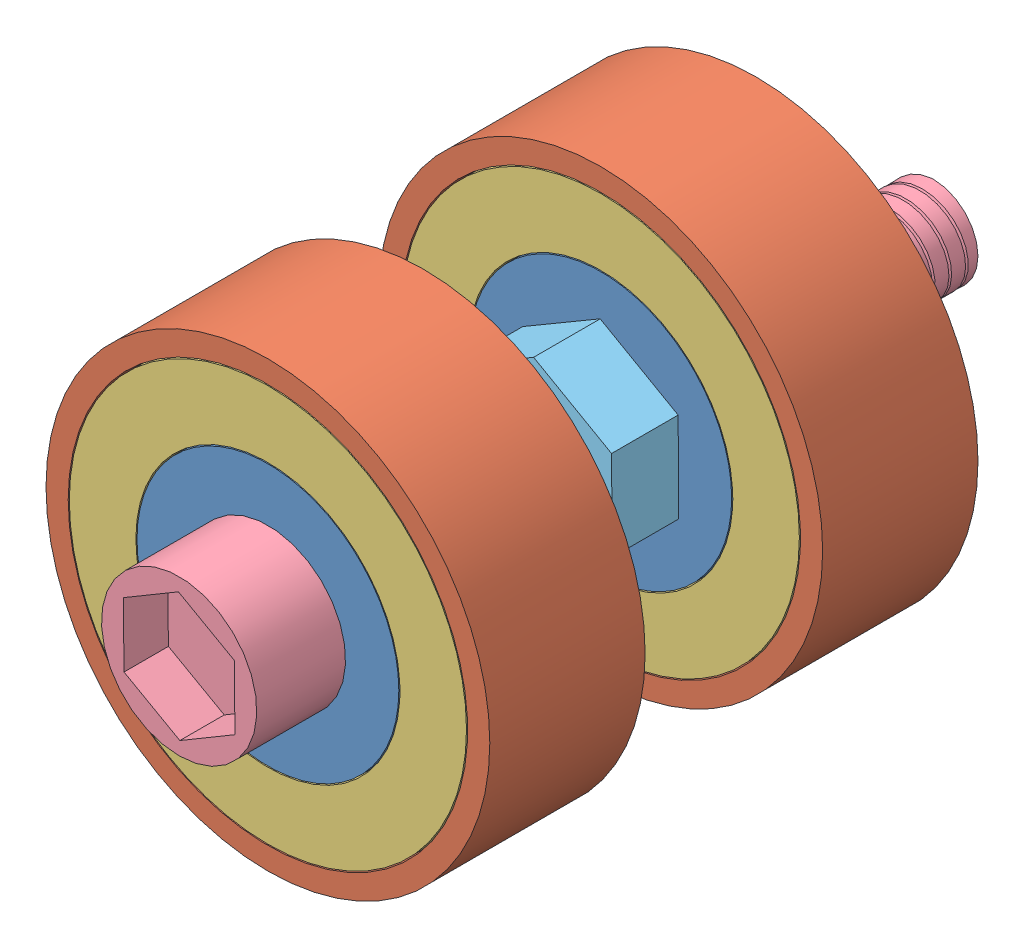
SolidWorks assembly 上导轮, configuration 默认. Lengths in mm.
Overall size (20 20 34).
11 component instances, 5 part files, 8 mates.
Components (placement in the parent):
- 轴承-1: 轴承 [默认] at (2.2867 -0.4125 10) size (20 20 7)
  - 轴承内圈-1: 轴承内圈 [默认] at (-5.0655 0.8032 6.5) size (11.8 11.8 7)
  - 轴承外圈-1: 轴承外圈 [默认] at (-5.0655 0.8032 6.5) size (20 20 7)
  - 轴承中圈-1: 轴承中圈 [默认] at (-5.0655 0.8032 6.5) size (17.9 17.9 7)
- 下螺栓-1: 下螺栓 [默认] at (-2.7788 0.3908 27.5) x (1 0 0) z (0 -1 0) size (7 34 7)
- 下部螺母-1: 下部螺母 [默认] at (-2.7788 0.3908 13.5) x (0.977413 0.211339 0) z (0 0 1) size (7.03 8.08 3.23)
- 下部螺母-2: 下部螺母 [默认] at (-2.7788 0.3908 8.5) size (7.03 8.08 3.23)
- 轴承-2: 轴承 [默认] at (2.2867 -0.4125 -5) size (20 20 7)
  - 轴承内圈-1: 轴承内圈 [默认] at (-5.0655 0.8032 6.5) size (11.8 11.8 7)
  - 轴承外圈-1: 轴承外圈 [默认] at (-5.0655 0.8032 6.5) size (20 20 7)
  - 轴承中圈-1: 轴承中圈 [默认] at (-5.0655 0.8032 6.5) size (17.9 17.9 7)
Mates (geometry in assembly coordinates):
- 重合3: coincident: plane of ? through (-2.7788 0.3908 23.5) normal (0 0 1); plane of 下螺栓-1 through (-2.7788 0.3908 23.5) normal (0 0 -1)
- 同心4: concentric: cylinder of ? through (-2.7788 0.3908 23.5) axis (0 0 -1) radius 2; cylinder of 下螺栓-1 through (-2.7788 0.3908 -6.5) axis (0 0 1) radius 2
- 同心5: concentric: cylinder of assembly; cylinder of assembly; cylinder of 下螺栓-1 through (-2.7788 0.3908 -6.5) axis (0 0 1) radius 2; cylinder of 下部螺母-1 through (-2.7788 0.3908 13.5) axis (0 0 1) radius 2
- 重合4: coincident: plane of ? through (-2.7788 0.3908 16.5) normal (0 0 -1); plane of 下部螺母-1 through (-2.7788 0.3908 16.5) normal (0 0 1)
- 同心6: concentric: cylinder of assembly; cylinder of assembly; cylinder of 下螺栓-1 through (-2.7788 0.3908 -6.5) axis (0 0 1) radius 2; cylinder of 下部螺母-2 through (-2.7788 0.3908 8.5) axis (0 0 1) radius 2
- 距离1: distance = 2 mm: plane of assembly; plane of assembly; plane of 下部螺母-2 through (-2.7788 0.3908 11.5) normal (0 0 1); plane of 下部螺母-1 through (-2.7788 0.3908 13.5) normal (0 0 -1)
- 同心7: concentric: cylinder of 下螺栓-1 through (-2.7788 0.3908 -6.5) axis (0 0 1) radius 2; cylinder of ? through (-2.7788 0.3908 8.5) axis (0 0 -1) radius 2
- 重合6: coincident: plane of 下部螺母-2 through (-2.7788 0.3908 8.5) normal (0 0 -1); plane of ? through (-2.7788 0.3908 8.5) normal (0 0 1)
